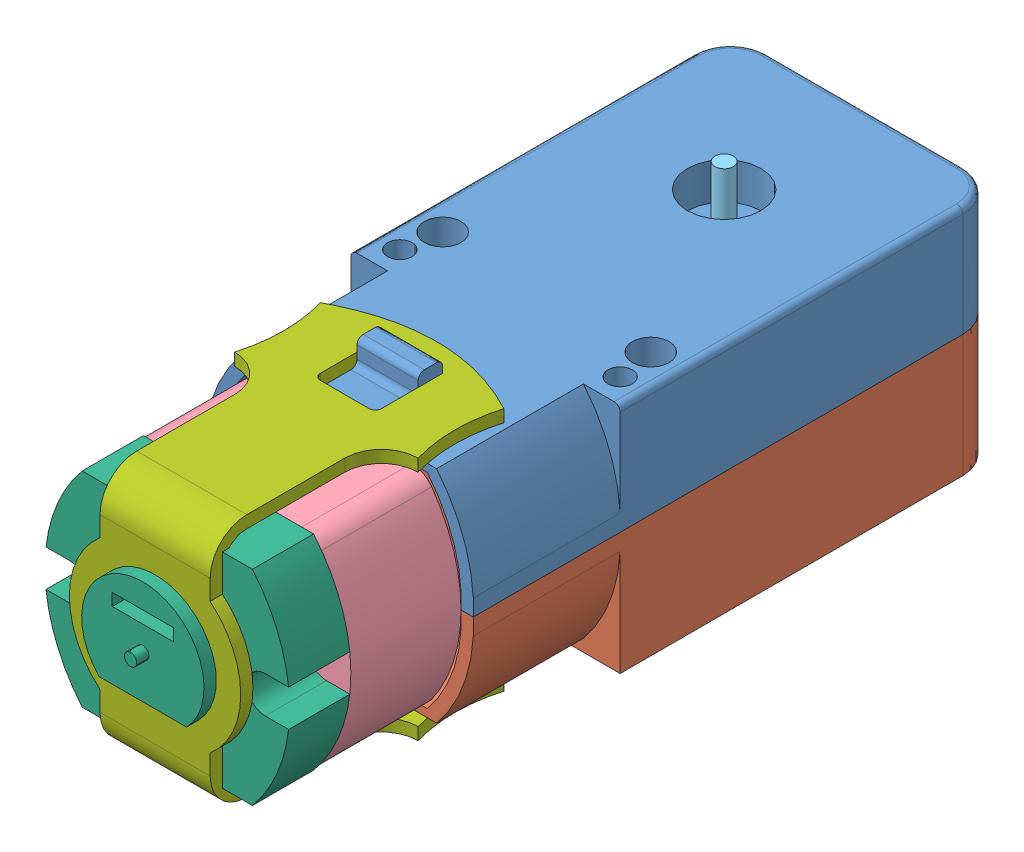
SolidWorks assembly Montagem motor, configuration Default. Lengths in mm.
Overall size (22 29.25 65).
7 component instances, 7 part files, 17 mates.
Components (placement in the parent):
- capa 1 (amarela)-2: capa 1 (amarela) [Default] at (-35.0993 65.3634 43.736) x (0 0 -1) z (1 0 0) size (48 11 22)
- capa 2 (amarela)-2: capa 2 (amarela) [Default] at (-57.0993 65.3634 43.736) x (0 0 -1) z (-1 0 0) size (48 11.5 22)
- pino motor-1: pino motor [Default] at (-46.0993 55.6134 23.736) x (-0.511614 0 0.859215) z (0.859215 0 0.511614) size (5 8.5 5)
- base1 (cinza)-1: base1 (cinza) [Default] at (-46.1006 65.3628 55.736) size (20 16.72 9)
- pino 2 (cinza)-1: pino 2 (cinza) [Default] at (-46.0993 71.3634 24.236) size (1.5 5 1.5)
- Ponta (preto)-2: Ponta (preto) [Default] at (-46.1006 65.3628 64.736) x (-1 0 0) z (0 0 1) size (19.83 16.72 8)
- suporte motor (acrílico)-2: suporte motor (acrílico) [Default] at (-38.6006 55.3628 47.736) x (0 -1 0) z (-1 0 0) size (20 23 15)
Mates (geometry in assembly coordinates):
- Coincident8: coincident anti-aligned: plane of capa 1 (amarela)-2 through (-35.0993 65.3634 43.736) normal (0 -1 0); plane of capa 2 (amarela)-2 through (-57.0993 65.3634 43.736) normal (0 1 0)
- Coincident9: coincident aligned: plane of capa 1 (amarela)-2 through (-43.5993 65.3634 7.736) normal (1 0 0); plane of capa 2 (amarela)-2 through (-43.5993 65.3634 7.736) normal (1 0 0)
- Coincident10: coincident aligned: plane of capa 1 (amarela)-2 through (-35.0993 65.3634 7.736) normal (0 0 -1); plane of capa 2 (amarela)-2 through (-57.0993 65.3634 7.736) normal (0 0 -1)
- Coincident12: coincident aligned: plane of capa 2 (amarela)-2 through (-46.0993 55.1134 23.736) normal (0 -1 0); plane of pino motor-1 through (-46.0993 55.1134 23.736) normal (0 -1 0)
- Coincident13: coincident aligned: cylinder of capa 2 (amarela)-2 through (-46.0993 60.3634 23.736) axis (0 -1 0) radius 2.5; circle of pino motor-1
- Coincident14: coincident anti-aligned: plane of capa 1 (amarela)-2 through (-53.3314 73.7228 45.736) normal (0 -1 0); plane of base1 (cinza)-1 through (-46.1006 73.7228 64.736) normal (0 1 0)
- Parallel1: parallel anti-aligned: cylinder of capa 1 (amarela)-2 through (-48.0819 66.0359 45.736) axis (0 0 1) radius 12; cylinder of base1 (cinza)-1 through (-49.1006 65.3628 64.736) axis (0 0 -1) radius 13
- Parallel4: parallel anti-aligned: cylinder of capa 1 (amarela)-2 through (-48.0819 66.0359 45.736) axis (0 0 1) radius 12; cylinder of base1 (cinza)-1 through (-49.1006 65.3628 64.736) axis (0 0 -1) radius 13
- Coincident15: coincident: point of capa 2 (amarela)-2; circle of base1 (cinza)-1
- Coincident19: coincident aligned: circle of capa 1 (amarela)-2; circle of pino 2 (cinza)-1
- Coincident25: coincident: plane of base1 (cinza)-1 through (-46.1006 65.3628 64.736) normal (0 0 1); plane of Ponta (preto)-2 through (-46.1006 65.3628 64.736) normal (0 0 -1)
- Coincident26: coincident: line of base1 (cinza)-1 through (-52.0756 57.0028 64.736) axis (1 0 0); line of Ponta (preto)-2 through (-39.1452 57.0028 64.736) axis (-1 0 0)
- Concentric7: concentric aligned: cylinder of base1 (cinza)-1 through (-43.1006 65.3628 64.736) axis (0 0 -1) radius 13; cylinder of Ponta (preto)-2 through (-43.1006 65.3628 69.736) axis (0 0 -1) radius 13
- Coincident34: coincident: plane of Ponta (preto)-2 through (-42.5299 61.8628 71.736) normal (0 -1 0); plane of suporte motor (acrílico)-2 through (-49.6713 61.8628 47.736) normal (0 1 0)
- Concentric8: concentric: cylinder of Ponta (preto)-2 through (-46.1006 65.3628 71.736) axis (0 0 -1) radius 5; cylinder of suporte motor (acrílico)-2 through (-46.1006 65.3628 47.736) axis (0 0 1) radius 5
- Concentric9: concentric: cylinder of Ponta (preto)-2 through (-46.1006 65.3628 71.736) axis (0 0 -1) radius 5; cylinder of suporte motor (acrílico)-2 through (-46.1006 65.3628 47.736) axis (0 0 1) radius 5
- Coincident35: coincident anti-aligned: plane of Ponta (preto)-2 through (-46.1006 65.3628 69.736) normal (0 0 1); plane of suporte motor (acrílico)-2 through (-53.6006 58.3628 69.736) normal (0 0 -1)
